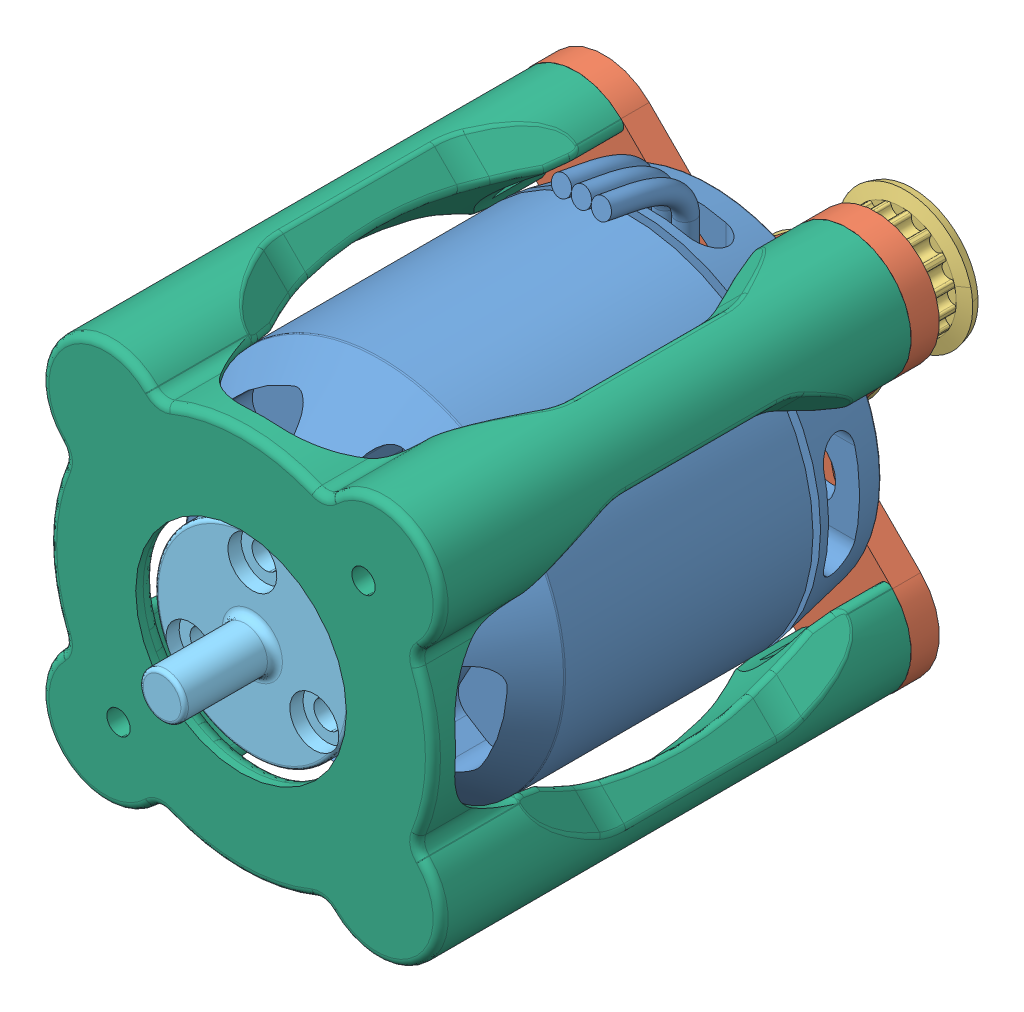
SolidWorks assembly Motor Assembly D, configuration Default. Lengths in mm.
Overall size (96.17 96.17 100.25).
8 component instances, 6 part files, 11 mates.
Components (placement in the parent):
- Turnigy 5055 280-1: Turnigy 5055 280 [Default] at (-117.8706 30.9479 46.9744) size (49 55.47 80)
- Motor Face Plate and Mount-1: Motor Face Plate and Mount [Default] at (-117.8706 30.9479 19.9744) x (0.707107 -0.707107 0) z (0.707107 0.707107 0) size (68 3.75 68)
- GPA16MR3090_K_P6-1: GPA16MR3090_K_P6 [Default] at (-117.8706 30.9479 -7.2756) x (0 0 1) z (0.99774 0.067193 0) size (23 18 18)
  - _GPA16MR3090_K_P6_b_2-1: _GPA16MR3090_K_P6_b_2 [Default] at origin size (23 18 18)
  - _SET_SCREW4_3_4-1: _SET_SCREW4_3_4 [Default] at (18 3 0) x (0 -1 0) z (-1 0 0) size (3 4 4)
  - _SET_SCREW4_3_4-2: _SET_SCREW4_3_4 [Default] at (18 -1.5 -2.5981) x (0 0.5 0.866025) z (-1 0 0) size (3 4 4)
- Screw on Encoder Shaft-1: Screw on Encoder Shaft [Default] at (-117.8706 30.9479 73.9744) x (1 0 0) z (0 -1 0) size (26 19 26)
- Encoder Mount RevC-1: Encoder Mount RevC [Default] at (-117.8706 30.9479 79.4744) x (-0.707107 0.707107 0) z (0 0 -1) size (68 68 62.5)
Mates (geometry in assembly coordinates):
- Concentric2: concentric aligned: cylinder of Turnigy 5055 280-1 through (-109.0318 39.7868 19.9744) axis (0 0 -1) radius 1.65; cylinder of Motor Face Plate and Mount-1 through (-109.0318 39.7868 16.2244) axis (0 0 -1) radius 2.15
- Concentric3: concentric aligned: cylinder of Turnigy 5055 280-1 through (-126.7095 22.1091 19.9744) axis (0 0 -1) radius 1.65; cylinder of Motor Face Plate and Mount-1 through (-126.7095 22.1091 16.2244) axis (0 0 -1) radius 2.15
- Concentric4: concentric anti-aligned: cylinder of Turnigy 5055 280-1 through (-117.8706 30.9479 -1.0256) axis (0 0 1) radius 3; cylinder of GPA16MR3090_K_P6-1/_GPA16MR3090_K_P6_b_2-1 through (-117.8706 30.9479 15.7244) axis (0 0 -1) radius 3
- Coincident2: coincident anti-aligned: plane of Turnigy 5055 280-1 through (-117.8706 30.9479 19.9744) normal (0 0 -1); plane of Motor Face Plate and Mount-1 through (-135.9019 12.9167 19.9744) normal (0 0 1)
- Distance1: distance = 0.5 mm anti-aligned: plane of Motor Face Plate and Mount-1 through (-135.9019 12.9167 16.2244) normal (0 0 -1); plane of GPA16MR3090_K_P6-1/_GPA16MR3090_K_P6_b_2-1 through (-117.2793 22.1678 15.7244) normal (0 0 1)
- Concentric5: concentric anti-aligned: cylinder of Turnigy 5055 280-1 through (-117.8706 30.9479 73.9744) axis (0 0 1) radius 7; cylinder of Screw on Encoder Shaft-1 through (-117.8706 30.9479 79.1244) axis (0 0 -1) radius 7.165
- Concentric6: concentric aligned: cylinder of Turnigy 5055 280-1 through (-117.8706 40.4479 73.9744) axis (0 0 1) radius 1.025; cylinder of Screw on Encoder Shaft-1 through (-117.8706 40.4479 80.9744) axis (0 0 1) radius 1.8
- Coincident4: coincident anti-aligned: plane of Turnigy 5055 280-1 through (-117.8706 30.9479 73.9744) normal (0 0 1); plane of Screw on Encoder Shaft-1 through (-117.8706 30.9479 73.9744) normal (0 0 -1)
- Concentric7: concentric anti-aligned: cylinder of Motor Face Plate and Mount-1 through (-138.3767 10.4419 16.2244) axis (0 0 1) radius 1.95; cylinder of Encoder Mount RevC-1 through (-138.3767 10.4419 19.9744) axis (0 0 -1) radius 2.9
- Concentric9: concentric anti-aligned: cylinder of Encoder Mount RevC-1 through (-97.3646 51.454 19.9744) axis (0 0 -1) radius 2.9; cylinder of Motor Face Plate and Mount-1 through (-97.3646 51.454 16.2244) axis (0 0 1) radius 1.95
- Coincident5: coincident anti-aligned: plane of Motor Face Plate and Mount-1 through (-135.9019 12.9167 19.9744) normal (0 0 1); plane of Encoder Mount RevC-1 through (-117.8706 30.9479 19.9744) normal (0 0 -1)
